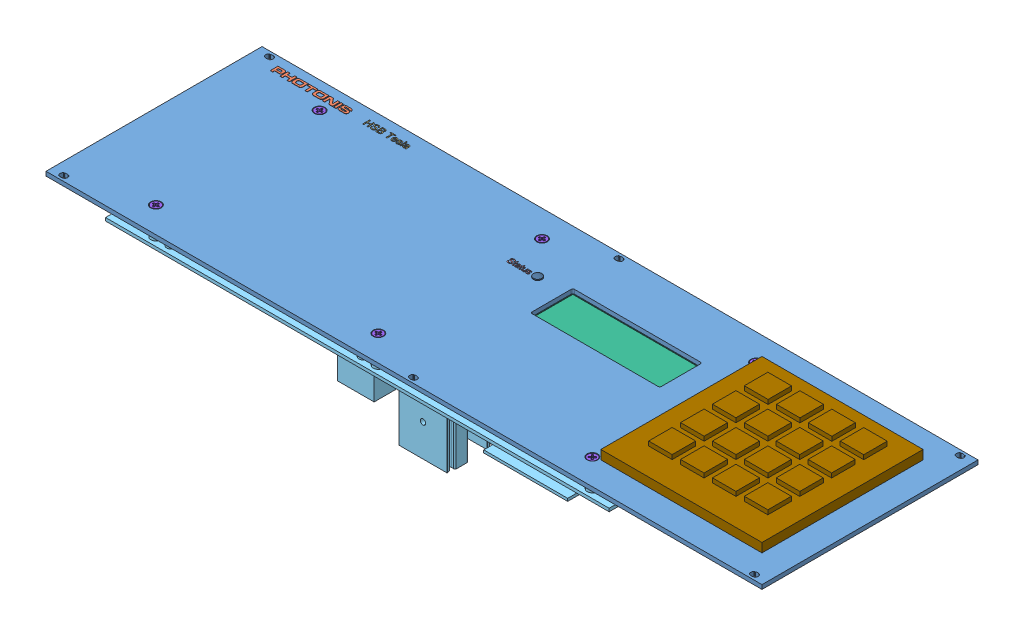
SolidWorks assembly MLA-0387-M13, configuration Default. Lengths in mm.
Overall size (426.52 63.69 128.7).
25 component instances, 13 part files, 41 mates.
Components (placement in the parent):
- MLA-0387-M12-1: MLA-0387-M12 [Default] at (-31.2027 -157.9839 598.0559) size (426.52 2.65 128.7)
  - MLA-0387-M1-1: MLA-0387-M1 [Default] at (-7.8975 -174.6729 597.0963) size (426.52 2.5 128.7)
  - LOGO PHOTONIS-1: LOGO PHOTONIS [Default] at (9.7425 205.5771 259.7963) x (1 0 0) z (0 1 0) size (45.16 4.45 0.15)
  - Tesla text-1: Tesla text [Default] at (64.2855 205.4271 259.8791) size (25.85 0.1 4.1)
  - Status text-1: Status text [Default] at (178.1079 205.4271 288.0463) size (13.33 0.1 3.59)
- MLA-0387-P1-PB1-3: MLA-0387-P1-PB1 [Default] at (-11.3802 30.9332 966.1522) x (1 0 0) z (0 1 0) size (300 107.5 53.19)
- NHD-0420D3Z-FL-GBW-V3-1: NHD-0420D3Z-FL-GBW-V3 [Default] at (170.3699 33.9432 922.6522) x (1 0 0) z (0 1 0) size (98 60 10.6)
- pan_head_phillip_M2x4-1: pan_head_phillip_M2x4 [Default] at (172.8699 35.5432 865.1522) x (1 0 0) z (0 0 1) size (4 9.78 4)
- pan_head_phillip_M2x4-2: pan_head_phillip_M2x4 [Default] at (265.8699 35.5432 865.1522) x (1 0 0) z (0 0 1) size (4 9.78 4)
- pan_head_phillip_M2x4-3: pan_head_phillip_M2x4 [Default] at (265.8699 35.5432 920.1522) x (1 0 0) z (0 0 1) size (4 9.78 4)
- pan_head_phillip_M2x4-4: pan_head_phillip_M2x4 [Default] at (172.8699 35.5432 920.1522) x (1 0 0) z (0 0 1) size (4 9.78 4)
- SCREW_ISO 7046-1: SCREW_ISO 7046 [VIJAK M 3x 10] at (13.6199 47.4432 863.6522) x (0 -1 0) z (0 0 1) size (10 5.6 5.6)
- SCREW_ISO 7046-2: SCREW_ISO 7046 [VIJAK M 3x 10] at (13.6199 47.4432 961.1522) x (0 -1 0) z (1 0 0) size (10 5.6 5.6)
- SCREW_ISO 7046-3: SCREW_ISO 7046 [VIJAK M 3x 10] at (146.1199 47.4432 961.1522) x (0 -1 0) z (0 0 1) size (10 5.6 5.6)
- SCREW_ISO 7046-4: SCREW_ISO 7046 [VIJAK M 3x 10] at (146.1199 47.4432 863.6522) x (0 -1 0) z (0 0 1) size (10 5.6 5.6)
- SCREW_ISO 7046-5: SCREW_ISO 7046 [VIJAK M 3x 10] at (273.6199 47.4432 863.6522) x (0 -1 0) z (0 0 1) size (10 5.6 5.6)
- SCREW_ISO 7046-6: SCREW_ISO 7046 [VIJAK M 3x 10] at (273.6199 47.3028 961.1522) x (0 -1 0) z (-0.743067 0 0.669217) size (10 5.6 5.6)
- Storm_7016010-2: Storm_7016010 [Default] at (277.7099 47.4432 960.2022) x (1 0 0) z (0 1 0) size (96 96 22)
- PLW5-500-1: PLW5-500 [Default] at (164.6199 47.4432 884.7422) size (5.25 13.97 5.07)
- MLA-0387-M7-1: MLA-0387-M7 [Default] at (17.6197 38.9432 966.1523) x (1 0 0) z (0 0 1) size (124.5 3 107.5)
- M2_5x8_Pan_head-1: M2_5x8_Pan_head [Default] at (22.6197 41.9432 863.6523) x (0 -1 0) z (-0.546944 0 0.837169) size (13.3 7.99 5.14)
- M2_5x8_Pan_head-2: M2_5x8_Pan_head [Default] at (22.6197 41.9432 961.1523) x (0 -1 0) z (-0.546944 0 0.837169) size (13.3 7.99 5.14)
- M2_5x8_Pan_head-3: M2_5x8_Pan_head [Default] at (137.1197 41.9432 863.6523) x (0 -1 0) z (-0.546944 0 0.837169) size (13.3 7.99 5.14)
- M2_5x8_Pan_head-4: M2_5x8_Pan_head [Default] at (137.1197 41.9432 961.1523) x (0 -1 0) z (-0.546944 0 0.837169) size (13.3 7.99 5.14)
- MLA-0387-C0-1: MLA-0387-C0 [Default] at (-12.3672 48.8231 1001.0043)
Mates (geometry in assembly coordinates):
- Concentric30: concentric aligned: cone of MLA-0387-M12-1/MLA-0387-M1-1 through (13.6199 47.4432 863.6522) axis (0 -1 0); cone of SCREW_ISO 7046-1 through (13.6199 45.9432 863.6522) axis (0 -1 0)
- Coincident48: coincident aligned: plane of MLA-0387-M12-1/MLA-0387-M1-1 through (-31.0198 47.4432 892.0763) normal (0 1 0); plane of SCREW_ISO 7046-1 through (13.6199 47.4432 863.6522) normal (0 1 0)
- Concentric31: concentric aligned: cone of MLA-0387-M12-1/MLA-0387-M1-1 through (13.6199 47.4432 961.1522) axis (0 -1 0); cone of SCREW_ISO 7046-2 through (13.6199 45.9432 961.1522) axis (0 -1 0)
- Coincident49: coincident aligned: plane of MLA-0387-M12-1/MLA-0387-M1-1 through (-31.0198 47.4432 892.0763) normal (0 1 0); plane of SCREW_ISO 7046-2 through (13.6199 47.4432 961.1522) normal (0 1 0)
- Concentric32: concentric aligned: cone of MLA-0387-M12-1/MLA-0387-M1-1 through (146.1199 47.4432 961.1522) axis (0 -1 0); cone of SCREW_ISO 7046-3 through (146.1199 45.9432 961.1522) axis (0 -1 0)
- Coincident50: coincident aligned: plane of MLA-0387-M12-1/MLA-0387-M1-1 through (-31.0198 47.4432 892.0763) normal (0 1 0); plane of SCREW_ISO 7046-3 through (146.1199 47.4432 961.1522) normal (0 1 0)
- Concentric33: concentric aligned: cone of MLA-0387-M12-1/MLA-0387-M1-1 through (146.1199 47.4432 863.6522) axis (0 -1 0); cone of SCREW_ISO 7046-4 through (146.1199 45.9432 863.6522) axis (0 -1 0)
- Coincident51: coincident aligned: plane of MLA-0387-M12-1/MLA-0387-M1-1 through (-31.0198 47.4432 892.0763) normal (0 1 0); plane of SCREW_ISO 7046-4 through (146.1199 47.4432 863.6522) normal (0 1 0)
- Concentric34: concentric aligned: cone of MLA-0387-M12-1/MLA-0387-M1-1 through (273.6199 47.4432 863.6522) axis (0 -1 0); cone of SCREW_ISO 7046-5 through (273.6199 45.9432 863.6522) axis (0 -1 0)
- Coincident52: coincident aligned: plane of MLA-0387-M12-1/MLA-0387-M1-1 through (-31.0198 47.4432 892.0763) normal (0 1 0); plane of SCREW_ISO 7046-5 through (273.6199 47.4432 863.6522) normal (0 1 0)
- Coincident53: coincident: circle of MLA-0387-M12-1/MLA-0387-M1-1; cone of SCREW_ISO 7046-6 through (273.6199 45.8028 961.1522) axis (0 -1 0)
- Concentric36: concentric aligned: cylinder of MLA-0387-M12-1/MLA-0387-M1-1 through (146.1199 47.4432 863.6522) axis (0 -1 0) radius 1.75; cylinder of MLA-0387-P1-PB1-3 through (146.1198 38.5432 863.6522) axis (0 -1 0) radius 3
- Concentric37: concentric aligned: circle of MLA-0387-M12-1/MLA-0387-M1-1; circle of MLA-0387-P1-PB1-3
- Coincident55: coincident anti-aligned: plane of MLA-0387-M12-1/MLA-0387-M1-1 through (-31.0198 44.9432 892.0763) normal (0 -1 0); plane of MLA-0387-P1-PB1-3 through (146.1198 44.9432 863.6522) normal (0 1 0)
- Concentric38: concentric aligned: cylinder of MLA-0387-P1-PB1-3 through (172.8699 29.5432 865.1522) axis (0 1 0) radius 2.175; cylinder of NHD-0420D3Z-FL-GBW-V3-1 through (172.8699 33.9432 865.1522) axis (0 1 0) radius 1.25
- Coincident57: coincident aligned: circle of MLA-0387-P1-PB1-3; plane of NHD-0420D3Z-FL-GBW-V3-1 through (170.3699 33.9432 922.6522) normal (0 -1 0)
- Concentric40: concentric aligned: cylinder of MLA-0387-P1-PB1-3 through (265.8699 29.5432 865.1522) axis (0 1 0) radius 2.175; cylinder of NHD-0420D3Z-FL-GBW-V3-1 through (265.8699 33.9432 865.1522) axis (0 1 0) radius 1.25
- Concentric41: concentric anti-aligned: cylinder of MLA-0387-P1-PB1-3 through (172.8699 29.5432 865.1522) axis (0 1 0) radius 2.175; cylinder of pan_head_phillip_M2x4-1 through (172.8699 37.3282 865.1522) axis (0 -1 0) radius 2
- Coincident58: coincident anti-aligned: plane of NHD-0420D3Z-FL-GBW-V3-1 through (170.3699 35.5432 922.6522) normal (0 1 0); plane of pan_head_phillip_M2x4-1 through (172.8699 35.5432 865.1522) normal (0 -1 0)
- Concentric42: concentric anti-aligned: cylinder of MLA-0387-P1-PB1-3 through (265.8699 29.5432 865.1522) axis (0 1 0) radius 2.175; cylinder of pan_head_phillip_M2x4-2 through (265.8699 37.3282 865.1522) axis (0 -1 0) radius 2
- Coincident59: coincident anti-aligned: plane of NHD-0420D3Z-FL-GBW-V3-1 through (170.3699 35.5432 922.6522) normal (0 1 0); plane of pan_head_phillip_M2x4-2 through (265.8699 35.5432 865.1522) normal (0 -1 0)
- Concentric43: concentric anti-aligned: cylinder of MLA-0387-P1-PB1-3 through (265.8699 29.5432 920.1522) axis (0 1 0) radius 2.175; cylinder of pan_head_phillip_M2x4-3 through (265.8699 37.3282 920.1522) axis (0 -1 0) radius 2
- Coincident60: coincident anti-aligned: plane of NHD-0420D3Z-FL-GBW-V3-1 through (170.3699 35.5432 922.6522) normal (0 1 0); plane of pan_head_phillip_M2x4-3 through (265.8699 35.5432 920.1522) normal (0 -1 0)
- Concentric44: concentric anti-aligned: cylinder of MLA-0387-P1-PB1-3 through (172.8699 29.5432 920.1522) axis (0 1 0) radius 2.175; cylinder of pan_head_phillip_M2x4-4 through (172.8699 37.3282 920.1522) axis (0 -1 0) radius 2
- Coincident61: coincident anti-aligned: plane of NHD-0420D3Z-FL-GBW-V3-1 through (170.3699 35.5432 922.6522) normal (0 1 0); plane of pan_head_phillip_M2x4-4 through (172.8699 35.5432 920.1522) normal (0 -1 0)
- Concentric45: concentric anti-aligned: cylinder of MLA-0387-M12-1/MLA-0387-M1-1 through (293.7099 47.4432 880.2022) axis (0 -1 0) radius 1.75; cylinder of Storm_7016010-2 through (293.7099 33.4432 880.2022) axis (0 1 0) radius 1.5
- Concentric46: concentric anti-aligned: cylinder of MLA-0387-M12-1/MLA-0387-M1-1 through (357.7099 47.4432 944.2022) axis (0 -1 0) radius 1.75; cylinder of Storm_7016010-2 through (357.7099 33.4432 944.2022) axis (0 1 0) radius 1.5
- Coincident62: coincident anti-aligned: plane of MLA-0387-M12-1/MLA-0387-M1-1 through (-31.0198 47.4432 892.0763) normal (0 1 0); plane of Storm_7016010-2 through (277.7099 47.4432 960.2022) normal (0 -1 0)
- Coincident63: coincident anti-aligned: plane of MLA-0387-M12-1/MLA-0387-M1-1 through (-31.0198 47.4432 892.0763) normal (0 1 0); plane of PLW5-500-1 through (162.0879 47.4432 882.2102) normal (0 -1 0)
- Concentric47: concentric aligned: circle of MLA-0387-M12-1/MLA-0387-M1-1; cylinder of PLW5-500-1 through (164.6199 35.9288 884.7422) axis (0 1 0) radius 1.9304
- Concentric48: concentric anti-aligned: cylinder of MLA-0387-P1-PB1-3 through (22.6197 27.095 863.6523) axis (0 -1 0) radius 1.0065; cylinder of MLA-0387-M7-1 through (22.6197 38.9432 863.6523) axis (0 1 0) radius 1.5
- Concentric49: concentric anti-aligned: cylinder of MLA-0387-P1-PB1-3 through (137.1197 27.095 961.1523) axis (0 -1 0) radius 1.0065; cylinder of MLA-0387-M7-1 through (137.1197 38.9432 961.1523) axis (0 1 0) radius 1.5
- Coincident64: coincident anti-aligned: plane of MLA-0387-P1-PB1-3 through (139.6697 38.9432 961.1523) normal (0 1 0); plane of MLA-0387-M7-1 through (17.6197 38.9432 966.1523) normal (0 -1 0)
- Concentric50: concentric aligned: cylinder of MLA-0387-M7-1 through (22.6197 38.9432 863.6523) axis (0 1 0) radius 1.5; cylinder of M2_5x8_Pan_head-1 through (22.6197 36.5024 863.6523) axis (0 1 0) radius 1
- Coincident65: coincident anti-aligned: plane of MLA-0387-M7-1 through (17.6197 41.9432 966.1523) normal (0 1 0); plane of M2_5x8_Pan_head-1 through (23.6007 41.9432 862.1509) normal (0 -1 0)
- Concentric51: concentric aligned: cylinder of MLA-0387-M7-1 through (22.6197 38.9432 961.1523) axis (0 1 0) radius 1.5; cylinder of M2_5x8_Pan_head-2 through (22.6197 36.5024 961.1523) axis (0 1 0) radius 1
- Coincident66: coincident anti-aligned: plane of MLA-0387-M7-1 through (17.6197 41.9432 966.1523) normal (0 1 0); plane of M2_5x8_Pan_head-2 through (23.6007 41.9432 959.6509) normal (0 -1 0)
- Concentric52: concentric aligned: cylinder of MLA-0387-M7-1 through (137.1197 38.9432 863.6523) axis (0 1 0) radius 1.5; cylinder of M2_5x8_Pan_head-3 through (137.1197 36.5024 863.6523) axis (0 1 0) radius 1
- Coincident67: coincident anti-aligned: plane of MLA-0387-M7-1 through (17.6197 41.9432 966.1523) normal (0 1 0); plane of M2_5x8_Pan_head-3 through (138.1007 41.9432 862.1508) normal (0 -1 0)
- Concentric53: concentric aligned: cylinder of MLA-0387-M7-1 through (137.1197 38.9432 961.1523) axis (0 1 0) radius 1.5; cylinder of M2_5x8_Pan_head-4 through (137.1197 36.5024 961.1523) axis (0 1 0) radius 1
- Coincident68: coincident anti-aligned: plane of MLA-0387-M7-1 through (17.6197 41.9432 966.1523) normal (0 1 0); plane of M2_5x8_Pan_head-4 through (138.1007 41.9432 959.6508) normal (0 -1 0)
